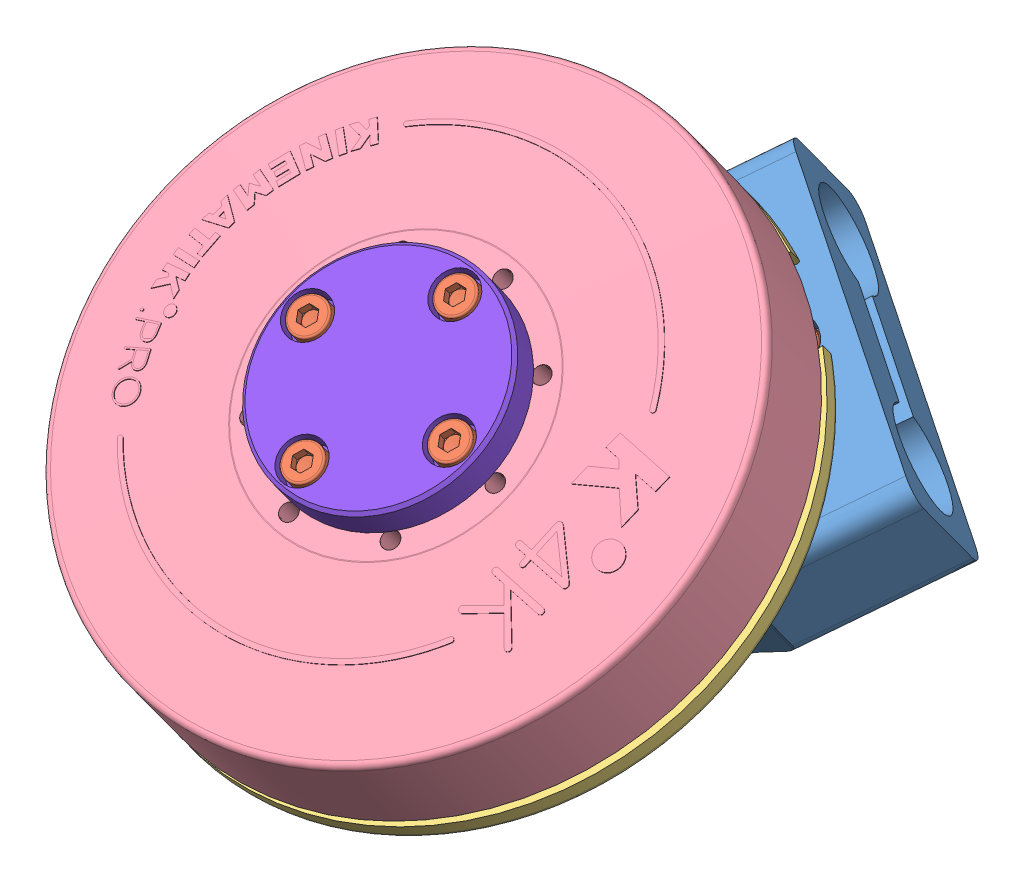
SolidWorks assembly motor_80_and_axis, configuration По умолчанию. Lengths in mm.
Overall size (133.98 129.98 133.98).
28 component instances, 11 part files, 55 mates.
Components (placement in the parent):
- Axis_pitch_short-1: Axis_pitch_short [Default] at (4.2659 56.9248 -1.5826) x (-0.567427 -0.468441 0.677193) z (-0.82193 0.371747 -0.431551) size (68 20 50)
- socket head cap screw_din-1: socket head cap screw_din [DIN 912 M4 x 16 --- 16N] at (21.2417 59.5124 26.245) x (-0.049588 -0.801478 -0.595965) z (-0.016405 -0.595965 0.802843) size (20 7 7)
- Motor8190_DYS-1: Motor8190_DYS [Default] at (-9.1554 68.3528 58.8249) x (-0.82193 0.371747 -0.431551) z (-0.567427 -0.468441 0.677193) size (115.95 27.86 115.95)
  - Stator-1: Stator [Default] at (-14.2107 17.4944 2.3302) size (87 7.3 86.61)
  - Rotor-1: Rotor [Default] at (-14.2107 15.8944 2.3302) x (0.429925 0 -0.902864) z (0 1 0) size (87 87 27.86)
- Washer_bearings-1: Washer_bearings [9mm] at (-0.4583 35.1333 46.574) x (0.179961 -0.594102 0.784) z (-0.982423 -0.068374 0.173695) size (40.8 9 40.8)
- radial ball bearing_68_am-1: radial ball bearing_68_am [AFBMA 20.1 - 38-20 - 18,SI,NC,18_68] at (-0.7062 31.1259 43.5942) x (0.049588 0.801478 0.595965) z (-0.016405 -0.595965 0.802843) size (10 32 32)
- socket button head cap screw_am-1: socket button head cap screw_am [B18.3.4M - 3 x 0.5 x 10 SBHCS --N] at (11.9376 30.6391 53.8519) x (0.049588 0.801478 0.595965) z (-0.016405 -0.595965 0.802843) size (11.65 5.7 5.7)
- socket button head cap screw_am-2: socket button head cap screw_am [B18.3.4M - 3 x 0.5 x 10 SBHCS --N] at (8.1201 43.242 37.2207) x (0.049588 0.801478 0.595965) z (-0.016405 -0.595965 0.802843) size (11.65 5.7 5.7)
- socket button head cap screw_am-3: socket button head cap screw_am [B18.3.4M - 3 x 0.5 x 10 SBHCS --N] at (-12.7203 41.7915 40.9053) x (0.049588 0.801478 0.595965) z (-0.016405 -0.595965 0.802843) size (11.65 5.7 5.7)
- socket button head cap screw_am-4: socket button head cap screw_am [B18.3.4M - 3 x 0.5 x 10 SBHCS --N] at (-8.9027 29.1887 57.5365) x (0.049588 0.801478 0.595965) z (-0.016405 -0.595965 0.802843) size (11.65 5.7 5.7)
- Axis_for_80th_motor-1: Axis_for_80th_motor [Default] at (1.555 67.6734 70.7702) x (0.986042 -0.134242 0.09849) z (0.049588 0.801478 0.595965) size (33 33 49)
- Axis_for_80th_motor_bearside-1: Axis_for_80th_motor_bearside [Default] at (-1.3211 21.1876 36.2043) x (-0.825331 0.368919 -0.427466) z (0.049588 0.801478 0.595965) size (20 20 24)
- socket set screw cone point_am-2: socket set screw cone point_am [B18.3.6M - M4 x 0.7 x 5 Hex Socket Cone Pt. SS --N] at (7.7752 31.1236 50.6103) x (-0.825331 0.368919 -0.427466) z (0.551539 0.364531 -0.750282) size (5 4 4)
- socket button head cap screw_am-14: socket button head cap screw_am [B18.3.4M - 3 x 0.5 x 10 SBHCS --N] at (-1.1054 24.674 38.7967) x (0.049588 0.801478 0.595965) z (0.284217 -0.583352 0.760868) size (11.65 5.7 5.7)
- Plate_roll-1: Plate_roll [Default] at (-55.2882 18.706 33.9642) x (0.825331 -0.368919 0.427466) z (-0.562467 -0.470671 0.679779) size (89.17 10 60) (hidden)
- socket head cap screw_din-2: socket head cap screw_din [DIN 912 M3 x 16 --- 16N] at (-0.4318 60.3888 80.7321) x (-0.049588 -0.801478 -0.595965) z (-0.016405 -0.595965 0.802843) size (19 5.5 5.5)
- socket head cap screw_din-4: socket head cap screw_din [DIN 912 M3 x 16 --- 16N] at (3.5417 74.9579 60.8084) x (-0.049588 -0.801478 -0.595965) z (-0.016405 -0.595965 0.802843) size (19 5.5 5.5)
- socket head cap screw_din-5: socket head cap screw_din [DIN 912 M3 x 16 --- 16N] at (13.8805 65.9953 72.0013) x (-0.049588 -0.801478 -0.595965) z (-0.016405 -0.595965 0.802843) size (19 5.5 5.5)
- socket head cap screw_din-7: socket head cap screw_din [DIN 912 M3 x 16 --- 16N] at (-10.7706 69.3514 69.5391) x (-0.049588 -0.801478 -0.595965) z (-0.016405 -0.595965 0.802843) size (19 5.5 5.5)
- socket button head cap screw_am-23: socket button head cap screw_am [B18.3.4M - 3 x 0.5 x 16 SBHCS --N] at (-4.3699 35.837 24.7271) x (0.049588 0.801478 0.595965) z (-0.016405 -0.595965 0.802843) size (17.65 5.7 5.7)
- socket button head cap screw_am-24: socket button head cap screw_am [B18.3.4M - 3 x 0.5 x 16 SBHCS --N] at (16.8437 26.2425 35.8652) x (0.049588 0.801478 0.595965) z (-0.016405 -0.595965 0.802843) size (17.65 5.7 5.7)
- socket button head cap screw_am-25: socket button head cap screw_am [B18.3.4M - 3 x 0.5 x 16 SBHCS --N] at (2.1987 14.1523 53.3431) x (0.049588 0.801478 0.595965) z (-0.016405 -0.595965 0.802843) size (17.65 5.7 5.7)
- socket button head cap screw_am-26: socket button head cap screw_am [B18.3.4M - 3 x 0.5 x 16 SBHCS --N] at (-19.0148 23.7468 42.205) x (0.049588 0.801478 0.595965) z (-0.016405 -0.595965 0.802843) size (17.65 5.7 5.7)
- socket head cap screw_din-8: socket head cap screw_din [DIN 912 M3 x 8 --- 8N] at (-2.7339 19.9408 27.9308) x (0.049588 0.801478 0.595965) z (-0.016405 -0.595965 0.802843) size (11 5.5 5.5)
- socket head cap screw_din-9: socket head cap screw_din [DIN 912 M3 x 8 --- 8N] at (-7.5066 15.947 33.699) x (0.049588 0.801478 0.595965) z (-0.016405 -0.595965 0.802843) size (11 5.5 5.5)
- socket head cap screw_din-10: socket head cap screw_din [DIN 912 M3 x 8 --- 8N] at (-0.5034 12.8167 37.3261) x (0.049588 0.801478 0.595965) z (-0.016405 -0.595965 0.802843) size (11 5.5 5.5)
- socket head cap screw_din-11: socket head cap screw_din [DIN 912 M3 x 8 --- 8N] at (4.2693 16.8104 31.558) x (0.049588 0.801478 0.595965) z (-0.016405 -0.595965 0.802843) size (11 5.5 5.5)
Mates (geometry in assembly coordinates):
- Концентричный1: concentric aligned: cylinder of Axis_pitch_short-1 through (21.2665 59.9132 26.543) axis (0.049588 0.801478 0.595965) radius 2.15; cylinder of socket head cap screw_din-1 through (22.8161 84.9594 45.1669) axis (0.049588 0.801478 0.595965) radius 3.5
- Совпадение1: coincident anti-aligned: plane of Axis_pitch_short-1 through (19.8234 55.2994 25.3171) normal (0.049588 0.801478 0.595965); plane of socket head cap screw_din-1 through (24.5386 56.133 23.8037) normal (-0.049588 -0.801478 -0.595965)
- Совпадение3: coincident anti-aligned: plane of Axis_pitch_short-1 through (-0.012 42.3466 51.9377) normal (0.049588 0.801478 0.595965); plane of Motor8190_DYS-1/Stator-1 through (24.6459 31.1942 64.8843) normal (-0.049588 -0.801478 -0.595965)
- Совпадение4: coincident anti-aligned: plane of Axis_pitch_short-1 through (-0.9542 27.1186 40.6144) normal (0.049588 0.801478 0.595965); plane of radial ball bearing_68_am-1 through (-15.1348 27.8227 40.8473) normal (-0.049588 -0.801478 -0.595965)
- Концентричный2: concentric aligned: cylinder of Axis_pitch_short-1 through (-3.2478 -9.9537 13.0482) axis (0.049588 0.801478 0.595965) radius 16; cylinder of radial ball bearing_68_am-1 through (-1.7296 14.5854 31.295) axis (0.049588 0.801478 0.595965) radius 16
- Совпадение5: coincident anti-aligned: plane of Motor8190_DYS-1/Stator-1 through (24.6459 31.1942 64.8843) normal (-0.049588 -0.801478 -0.595965); plane of Washer_bearings-1 through (-0.012 42.3466 51.9377) normal (0.049588 0.801478 0.595965)
- Концентричный3: concentric anti-aligned: cylinder of Motor8190_DYS-1/Rotor-1 through (0.4145 49.2394 57.063) axis (0.049588 0.801478 0.595965) radius 6.5; cylinder of Washer_bearings-1 through (-0.012 42.3466 51.9377) axis (-0.049588 -0.801478 -0.595965) radius 11
- Концентричный4: concentric aligned: cylinder of Motor8190_DYS-1/Stator-1 through (8.4994 49.3733 41.7798) axis (-0.049588 -0.801478 -0.595965) radius 1.25; cylinder of Washer_bearings-1 through (8.0531 42.16 36.4162) axis (-0.049588 -0.801478 -0.595965) radius 1.7
- Концентричный5: concentric aligned: cylinder of Washer_bearings-1 through (11.8707 29.5571 53.0473) axis (-0.049588 -0.801478 -0.595965) radius 1.7; cylinder of socket button head cap screw_am-1 through (11.9376 30.6391 53.8519) axis (-0.049588 -0.801478 -0.595965) radius 2.85
- Совпадение6: coincident anti-aligned: plane of Washer_bearings-1 through (12.3254 30.9516 56.168) normal (-0.049588 -0.801478 -0.595965); plane of socket button head cap screw_am-1 through (10.5215 32.036 54.8598) normal (0.049588 0.801478 0.595965)
- Концентричный6: concentric aligned: cylinder of Washer_bearings-1 through (8.0531 42.16 36.4162) axis (-0.049588 -0.801478 -0.595965) radius 1.7; cylinder of socket button head cap screw_am-2 through (8.1201 43.242 37.2207) axis (-0.049588 -0.801478 -0.595965) radius 2.85
- Совпадение7: coincident anti-aligned: plane of Washer_bearings-1 through (8.5078 43.5544 39.5369) normal (-0.049588 -0.801478 -0.595965); plane of socket button head cap screw_am-2 through (6.7039 44.6388 38.2287) normal (0.049588 0.801478 0.595965)
- Концентричный7: concentric aligned: cylinder of Washer_bearings-1 through (-12.7872 40.7095 40.1008) axis (-0.049588 -0.801478 -0.595965) radius 1.7; cylinder of socket button head cap screw_am-3 through (-12.7203 41.7915 40.9053) axis (-0.049588 -0.801478 -0.595965) radius 2.85
- Совпадение8: coincident anti-aligned: plane of Washer_bearings-1 through (-12.3325 42.104 43.2215) normal (-0.049588 -0.801478 -0.595965); plane of socket button head cap screw_am-3 through (-14.1364 43.1883 41.9133) normal (0.049588 0.801478 0.595965)
- Концентричный8: concentric aligned: cylinder of Washer_bearings-1 through (-8.9697 28.1067 56.7319) axis (-0.049588 -0.801478 -0.595965) radius 3.25; cylinder of socket button head cap screw_am-4 through (-8.9027 29.1887 57.5365) axis (-0.049588 -0.801478 -0.595965) radius 2.85
- Совпадение9: coincident anti-aligned: plane of Washer_bearings-1 through (-8.515 29.5012 59.8526) normal (-0.049588 -0.801478 -0.595965); plane of socket button head cap screw_am-4 through (-10.3189 30.5855 58.5444) normal (0.049588 0.801478 0.595965)
- Концентричный9: concentric anti-aligned: cylinder of Motor8190_DYS-1/Rotor-1 through (0.4145 49.2394 57.063) axis (0.049588 0.801478 0.595965) radius 6.5; cylinder of Axis_for_80th_motor-1 through (-0.8748 28.4009 41.5679) axis (-0.049588 -0.801478 -0.595965) radius 6.3
- Совпадение10: coincident anti-aligned: plane of Motor8190_DYS-1/Rotor-1 through (-1.8718 52.0107 83.7293) normal (0.049588 0.801478 0.595965); plane of Axis_for_80th_motor-1 through (3.9296 73.2815 54.6407) normal (-0.049588 -0.801478 -0.595965)
- Концентричный14: concentric aligned: cylinder of Motor8190_DYS-1/Rotor-1 through (3.2938 70.9505 57.8285) axis (0.049588 0.801478 0.595965) radius 1.25; cylinder of Axis_for_80th_motor-1 through (3.5417 74.9579 60.8084) axis (0.049588 0.801478 0.595965) radius 1.7
- Концентричный20: concentric anti-aligned: cylinder of Axis_for_80th_motor-1 through (-0.8748 28.4009 41.5679) axis (-0.049588 -0.801478 -0.595965) radius 6.3; cylinder of Axis_for_80th_motor_bearside-1 through (-0.8748 28.4009 41.5679) axis (0.049588 0.801478 0.595965) radius 6.5
- Совпадение20: coincident anti-aligned: plane of Axis_for_80th_motor-1 through (0.1265 32.0723 36.5472) normal (-0.049588 -0.801478 -0.595965); plane of Axis_for_80th_motor_bearside-1 through (-0.8748 28.4009 41.5679) normal (0.049588 0.801478 0.595965)
- Концентричный22: concentric aligned: cylinder of Axis_for_80th_motor_bearside-1 through (7.7752 31.1236 50.6103) axis (0.825331 -0.368919 0.427466) radius 1.65; cylinder of socket set screw cone point_am-2 through (18.2569 26.4383 56.0391) axis (0.825331 -0.368919 0.427466) radius 2
- Концентричный23: concentric aligned: cylinder of Axis_for_80th_motor_bearside-1 through (7.7752 31.1236 50.6103) axis (0.825331 -0.368919 0.427466) radius 1.65; cylinder of socket set screw cone point_am-2 through (18.2569 26.4383 56.0391) axis (0.825331 -0.368919 0.427466) radius 2
- Касательность2: tangent aligned: cylinder of Axis_for_80th_motor_bearside-1 through (-0.131 40.4231 50.5074) axis (-0.049588 -0.801478 -0.595965) radius 10; plane of socket set screw cone point_am-2 through (7.7752 31.1236 50.6103) normal (0.825331 -0.368919 0.427466)
- Концентричный24: concentric aligned: cylinder of Axis_for_80th_motor_bearside-1 through (-1.3211 21.1876 36.2043) axis (-0.049588 -0.801478 -0.595965) radius 1.7; cylinder of socket button head cap screw_am-14 through (-1.1054 24.674 38.7967) axis (-0.049588 -0.801478 -0.595965) radius 1.5
- Совпадение21: coincident anti-aligned: plane of Axis_for_80th_motor_bearside-1 through (-2.4266 26.6236 39.0534) normal (-0.049588 -0.801478 -0.595965); plane of socket button head cap screw_am-14 through (-2.4598 25.799 40.1651) normal (0.049588 0.801478 0.595965)
- Концентричный25: concentric anti-aligned: cylinder of Axis_pitch_short-1 through (-3.8294 -19.3534 6.0587) axis (0.049588 0.801478 0.595965) radius 20.5; cylinder of Washer_bearings-1 through (-0.012 42.3466 51.9377) axis (-0.049588 -0.801478 -0.595965) radius 20.4
- Концентричный26: concentric aligned: cylinder of Axis_pitch_short-1 through (2.826 24.291 60.8821) axis (0.049588 0.801478 0.595965) radius 1.6; cylinder of Washer_bearings-1 through (3.2723 31.5043 66.2457) axis (0.049588 0.801478 0.595965) radius 1.25
- Совпадение26: coincident anti-aligned: plane of Axis_for_80th_motor_bearside-1 through (-1.3211 21.1876 36.2043) normal (-0.049588 -0.801478 -0.595965); plane of Plate_roll-1 through (3.1499 19.1891 38.5199) normal (0.049588 0.801478 0.595965)
- Концентричный31: concentric aligned: cylinder of Axis_for_80th_motor_bearside-1 through (-2.4363 24.7497 31.5066) axis (-0.049588 -0.801478 -0.595965) radius 1.25; cylinder of Plate_roll-1 through (-2.7339 19.9408 27.9308) axis (-0.049588 -0.801478 -0.595965) radius 1.6
- Концентричный32: concentric aligned: cylinder of Axis_for_80th_motor_bearside-1 through (-0.2059 17.6255 40.9019) axis (-0.049588 -0.801478 -0.595965) radius 1.25; cylinder of Plate_roll-1 through (-0.5034 12.8167 37.3261) axis (-0.049588 -0.801478 -0.595965) radius 1.6
- Концентричный41: concentric aligned: cylinder of Axis_for_80th_motor-1 through (-0.4318 60.3888 80.7321) axis (0.049588 0.801478 0.595965) radius 3.25; cylinder of socket head cap screw_din-2 through (1.1426 85.8358 99.6539) axis (0.049588 0.801478 0.595965) radius 2.75
- Совпадение35: coincident anti-aligned: plane of Axis_for_80th_motor-1 through (1.0957 57.7562 79.1116) normal (0.049588 0.801478 0.595965); plane of socket head cap screw_din-2 through (2.1657 57.848 78.8991) normal (-0.049588 -0.801478 -0.595965)
- Концентричный43: concentric aligned: cylinder of Axis_for_80th_motor-1 through (3.5417 74.9579 60.8084) axis (0.049588 0.801478 0.595965) radius 3.25; cylinder of socket head cap screw_din-4 through (5.1161 100.4048 79.7302) axis (0.049588 0.801478 0.595965) radius 2.75
- Совпадение37: coincident anti-aligned: plane of Axis_for_80th_motor-1 through (5.0692 72.3252 59.1879) normal (0.049588 0.801478 0.595965); plane of socket head cap screw_din-4 through (6.1392 72.4171 58.9754) normal (-0.049588 -0.801478 -0.595965)
- Концентричный44: concentric aligned: cylinder of Axis_for_80th_motor-1 through (13.8805 65.9953 72.0013) axis (0.049588 0.801478 0.595965) radius 1.7; cylinder of socket head cap screw_din-5 through (15.4549 91.4423 90.9232) axis (0.049588 0.801478 0.595965) radius 2.75
- Совпадение38: coincident anti-aligned: plane of Axis_for_80th_motor-1 through (15.408 63.3627 70.3809) normal (0.049588 0.801478 0.595965); plane of socket head cap screw_din-5 through (16.478 63.4545 70.1683) normal (-0.049588 -0.801478 -0.595965)
- Совпадение40: coincident anti-aligned: plane of Axis_for_80th_motor-1 through (5.0692 72.3252 59.1879) normal (0.049588 0.801478 0.595965); plane of socket head cap screw_din-7 through (-8.1731 66.8106 67.7061) normal (-0.049588 -0.801478 -0.595965)
- Концентричный45: concentric aligned: cylinder of Axis_for_80th_motor-1 through (-10.7706 69.3514 69.5391) axis (0.049588 0.801478 0.595965) radius 1.7; cylinder of socket head cap screw_din-7 through (-9.1961 94.7983 88.461) axis (0.049588 0.801478 0.595965) radius 2.75
- Концентричный46: concentric anti-aligned: cylinder of Axis_pitch_short-1 through (-3.7426 45.9757 32.266) axis (0.049588 0.801478 0.595965) radius 1.6; cylinder of socket button head cap screw_am-23 through (-4.3699 35.837 24.7271) axis (-0.049588 -0.801478 -0.595965) radius 2.85
- Совпадение41: coincident anti-aligned: plane of Axis_pitch_short-1 through (-1.0037 26.3171 40.0184) normal (-0.049588 -0.801478 -0.595965); plane of socket button head cap screw_am-23 through (-5.786 37.2338 25.735) normal (0.049588 0.801478 0.595965)
- Совпадение42: coincident anti-aligned: plane of Axis_pitch_short-1 through (-1.0037 26.3171 40.0184) normal (-0.049588 -0.801478 -0.595965); plane of socket button head cap screw_am-24 through (15.4275 27.6393 36.8731) normal (0.049588 0.801478 0.595965)
- Концентричный47: concentric anti-aligned: cylinder of Axis_pitch_short-1 through (17.4709 36.3812 43.4041) axis (0.049588 0.801478 0.595965) radius 1.6; cylinder of socket button head cap screw_am-24 through (16.8437 26.2425 35.8652) axis (-0.049588 -0.801478 -0.595965) radius 2.85
- Концентричный48: concentric anti-aligned: cylinder of Axis_pitch_short-1 through (2.826 24.291 60.8821) axis (0.049588 0.801478 0.595965) radius 1.6; cylinder of socket button head cap screw_am-25 through (2.1987 14.1523 53.3431) axis (-0.049588 -0.801478 -0.595965) radius 2.85
- Совпадение43: coincident anti-aligned: plane of Axis_pitch_short-1 through (-1.0037 26.3171 40.0184) normal (-0.049588 -0.801478 -0.595965); plane of socket button head cap screw_am-25 through (0.7826 15.5491 54.351) normal (0.049588 0.801478 0.595965)
- Концентричный49: concentric anti-aligned: cylinder of Axis_pitch_short-1 through (-18.3875 33.8855 49.744) axis (0.049588 0.801478 0.595965) radius 1.6; cylinder of socket button head cap screw_am-26 through (-19.0148 23.7468 42.205) axis (-0.049588 -0.801478 -0.595965) radius 2.85
- Совпадение44: coincident anti-aligned: plane of Axis_pitch_short-1 through (-1.0037 26.3171 40.0184) normal (-0.049588 -0.801478 -0.595965); plane of socket button head cap screw_am-26 through (-20.4309 25.1436 43.213) normal (0.049588 0.801478 0.595965)
- Концентричный50: concentric aligned: cylinder of Plate_roll-1 through (-2.7339 19.9408 27.9308) axis (-0.049588 -0.801478 -0.595965) radius 3.25; cylinder of socket head cap screw_din-8 through (-4.3083 -5.5061 9.009) axis (-0.049588 -0.801478 -0.595965) radius 2.75
- Совпадение45: coincident anti-aligned: plane of Plate_roll-1 through (-1.2646 21.755 30.4027) normal (-0.049588 -0.801478 -0.595965); plane of socket head cap screw_din-8 through (-5.3314 22.4816 29.7638) normal (0.049588 0.801478 0.595965)
- Совпадение46: coincident anti-aligned: plane of Plate_roll-1 through (-1.2646 21.755 30.4027) normal (-0.049588 -0.801478 -0.595965); plane of socket head cap screw_din-9 through (-10.104 18.4878 35.532) normal (0.049588 0.801478 0.595965)
- Концентричный51: concentric aligned: cylinder of Plate_roll-1 through (-7.5066 15.947 33.699) axis (-0.049588 -0.801478 -0.595965) radius 1.6; cylinder of socket head cap screw_din-9 through (-9.081 -9.4999 14.7771) axis (-0.049588 -0.801478 -0.595965) radius 2.75
- Концентричный52: concentric aligned: cylinder of Plate_roll-1 through (-0.5034 12.8167 37.3261) axis (-0.049588 -0.801478 -0.595965) radius 1.6; cylinder of socket head cap screw_din-10 through (-2.0778 -12.6303 18.4042) axis (-0.049588 -0.801478 -0.595965) radius 2.75
- Совпадение47: coincident anti-aligned: plane of Plate_roll-1 through (-1.2646 21.755 30.4027) normal (-0.049588 -0.801478 -0.595965); plane of socket head cap screw_din-10 through (-3.1009 15.3575 39.1591) normal (0.049588 0.801478 0.595965)
- Концентричный53: concentric aligned: cylinder of Plate_roll-1 through (4.2693 16.8104 31.558) axis (-0.049588 -0.801478 -0.595965) radius 1.6; cylinder of socket head cap screw_din-11 through (2.6949 -8.6365 12.6361) axis (-0.049588 -0.801478 -0.595965) radius 2.75
- Совпадение48: coincident anti-aligned: plane of Plate_roll-1 through (-1.2646 21.755 30.4027) normal (-0.049588 -0.801478 -0.595965); plane of socket head cap screw_din-11 through (1.6718 19.3512 33.391) normal (0.049588 0.801478 0.595965)
